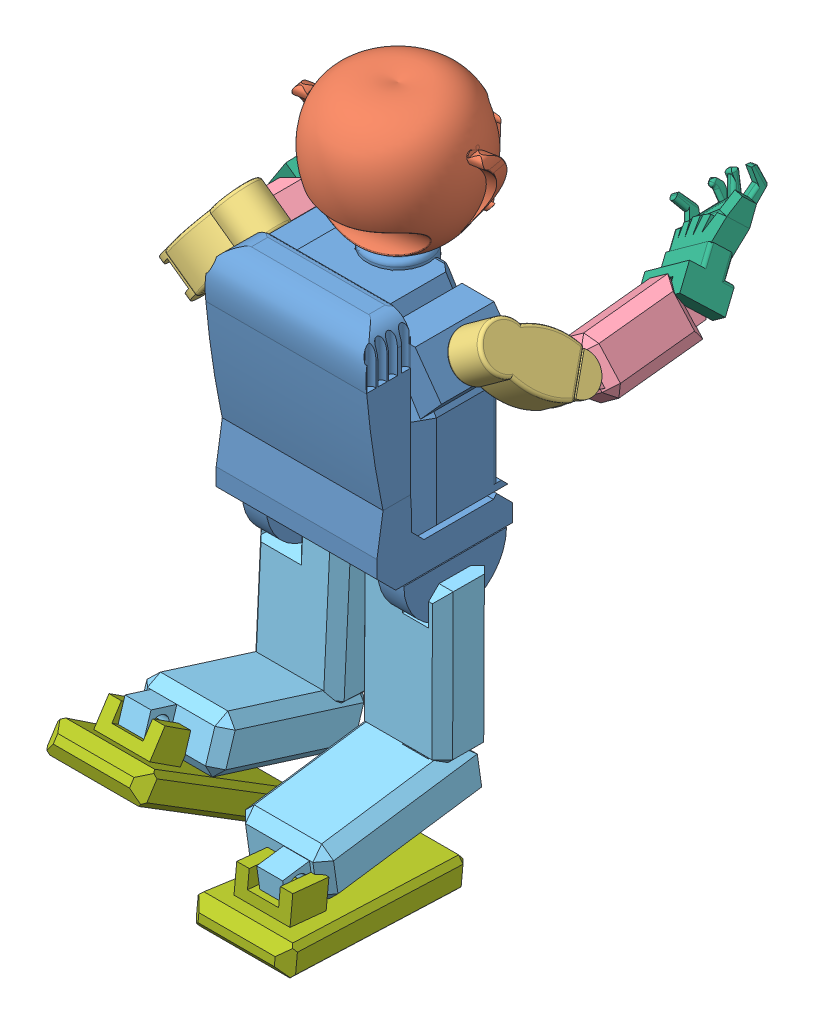
SolidWorks assembly Assem2, configuration Default. Lengths in mm.
Overall size (374.28 631.71 468.66).
14 component instances, 7 part files, 27 mates.
Components (placement in the parent):
- Part3-1: Part3 [Default] at (10.608 -20.5845 -192.5462) size (215.49 271.63 146.25)
- Part1-1: Part1 [Default] at (10.608 181.7095 -178.4472) x (0.182911 0 0.983129) z (-0.983129 0 0.182911) size (177.08 159.74 177.08)
- Part4-1: Part4 [Default] at (113.8396 66.1948 -165.3801) x (0.386781 -0.536178 -0.750275) z (0.811008 0.585035 0) size (102.94 60.36 51.55)
- Part4-2: Part4 [Default] at (-96.5936 60.6913 -146.4531) x (-0.568564 -0.788176 0.235612) z (-0.811008 0.585035 0) size (102.94 60.36 51.55)
- Part5-1: Part5 [Default] at (162.1933 57.4976 -215.127) x (0.583363 -0.808692 -0.075531) z (-0.811008 -0.585035 0) size (51.37 125.6 41.41)
- Part5-2: Part5 [Default] at (-134.9017 23.1874 -142.519) x (-0.584987 -0.810943 -0.01272) z (-0.811008 0.585035 0) size (51.37 125.6 41.41)
- Part6-2: Part6 [Default] at (60.772 -192.5534 -178.723) x (1 0 0) z (0 0.004453 0.99999) size (85 176.15 50)
- Part6-3: Part6 [Default] at (-39.5561 -191.1742 -127.4189) x (-1 0 0) z (0 -0.049279 -0.998785) size (85 176.15 50)
- Part6-4: Part6 [Default] at (61.3239 -314.0436 -93.1319) x (1 0 0) z (0 0.989849 0.14212) size (85 176.15 50)
- Part6-5: Part6 [Default] at (-40.108 -238.5894 -94.7079) x (-1 0 0) z (0 -0.954085 0.299535) size (85 176.15 50)
- Part7-1: Part7 [Default] at (132.6952 72.4721 -310.1946) x (0.811008 0.585035 0) z (0.442514 -0.613438 -0.654122) size (71.55 112.24 41.96)
- Part7-2: Part7 [Default] at (-133.5743 51.6475 -250.1902) x (0.811008 -0.585035 0) z (-0.576708 -0.799466 -0.168113) size (71.55 112.24 41.96)
- Part8-1: Part8 [Default] at (75.4814 -332.0717 -16.4181) x (1 0 0) z (0 0.099495 0.995038) size (95.64 54.98 186.47)
- Part8-2: Part8 [Default] at (-54.2655 -270.1317 -1.563) x (1 0 0) z (0 0.543742 0.839253) size (95.64 54.98 186.47)
Mates (geometry in assembly coordinates):
- Concentric1: concentric: cylinder of Part3-1 through (10.608 108.1735 -178.4472) axis (0 1 0) radius 12; cylinder of Part1-1 through (10.608 109.8979 -178.4472) axis (0 1 0) radius 12
- Concentric3: concentric: cylinder of Part3-1 through (102.1186 73.8965 -149.4154) axis (0.811008 0.585035 0) radius 10; cylinder of Part4-1 through (98.0636 70.9713 -149.4154) axis (0.811008 0.585035 0) radius 10
- Concentric4: concentric: cylinder of Part3-1 through (-76.8476 70.9713 -152.0195) axis (-0.811008 0.585035 0) radius 10; cylinder of Part4-2 through (-76.8476 70.9713 -152.0195) axis (-0.811008 0.585035 0) radius 10
- Concentric5: concentric: cylinder of Part4-1 through (137.3423 38.7419 -206.2509) axis (0.811008 0.585035 0) radius 3; cylinder of Part5-1 through (142.3114 42.3264 -206.2509) axis (0.811008 0.585035 0) radius 5
- Coincident1: coincident: plane of Part4-1 through (132.7421 55.5919 -243.6536) normal (0.811008 0.585035 0); plane of Part5-1 through (142.769 41.6921 -199.1001) normal (-0.811008 -0.585035 0)
- Coincident2: coincident: plane of Part3-1 through (93.0556 95.0067 -188.5462) normal (0.811008 0.585035 0); plane of Part4-1 through (110.3667 71.009 -197.4055) normal (-0.811008 -0.585035 0)
- Coincident3: coincident: plane of Part3-1 through (-71.8396 95.0067 -188.5462) normal (-0.811008 0.585035 0); plane of Part4-2 through (-104.4912 49.7432 -116.8114) normal (0.811008 -0.585035 0)
- Concentric6: concentric: cylinder of Part4-2 through (-129.9988 19.511 -133.6182) axis (-0.811008 0.585035 0) radius 3; cylinder of Part5-2 through (-155.2432 37.7214 -133.6182) axis (0.811008 -0.585035 0) radius 5
- Coincident4: coincident: plane of Part4-2 through (-139.6747 16.5708 -93.5959) normal (-0.811008 0.585035 0); plane of Part5-2 through (-135.1618 22.8269 -126.4324) normal (0.811008 -0.585035 0)
- Coincident5: coincident: plane of Part3-1 through (64.3776 -102.9946 -36.5462) normal (-1 0 0); plane of Part6-2 through (64.3776 -192.3307 -128.7235) normal (1 0 0)
- Parallel1: parallel: plane of Part3-1 through (89.608 -102.8804 -154.5768) normal (1 0 0); plane of Part6-2 through (89.3776 -192.3307 -128.7235) normal (-1 0 0)
- Concentric7: concentric: cylinder of Part3-1 through (89.608 -128.546 -154.7731) axis (-1 0 0) radius 10; cylinder of Part6-2 through (100.3776 -128.546 -154.7731) axis (-1 0 0) radius 10
- Coincident8: coincident: plane of Part3-1 through (-43.1616 -102.9946 -36.5462) normal (1 0 0); plane of Part6-3 through (-43.1616 -193.6381 -177.3581) normal (-1 0 0)
- Concentric9: concentric: cylinder of Part3-1 through (89.608 -128.546 -154.7731) axis (-1 0 0) radius 10; cylinder of Part6-3 through (-79.1616 -128.546 -154.7731) axis (1 0 0) radius 10
- Coincident9: coincident: circle of Part3-1; circle of Part1-1
- Concentric10: concentric: cylinder of Part6-2 through (105.9049 -280.9734 -152.9392) axis (-1 0 0) radius 10; cylinder of Part6-4 through (100.9295 -280.9734 -152.9392) axis (-1 0 0) radius 10
- Coincident11: coincident: plane of Part6-2 through (89.9295 -308.3759 -138.6125) normal (1 0 0); plane of Part6-4 through (89.9295 -264.5511 -86.0259) normal (-1 0 0)
- Concentric11: concentric: cylinder of Part6-3 through (-84.6889 -280.8517 -148.415) axis (1 0 0) radius 10; cylinder of Part6-5 through (-79.7135 -280.8517 -148.415) axis (1 0 0) radius 10
- Coincident12: coincident: plane of Part6-3 through (-68.7135 -308.9844 -161.2488) normal (-1 0 0); plane of Part6-5 through (-68.7135 -286.2937 -79.7312) normal (1 0 0)
- Concentric12: concentric: cylinder of Part5-1 through (204.9532 97.9546 -318.035) axis (-0.811008 -0.585035 0) radius 5; cylinder of Part7-1 through (165.5472 69.5284 -318.035) axis (-0.811008 -0.585035 0) radius 5
- Concentric13: concentric: cylinder of Part5-2 through (-86.8135 -9.8833 -245.7135) axis (-0.811008 0.585035 0) radius 5; cylinder of Part7-2 through (-126.5529 18.7834 -245.7135) axis (-0.811008 0.585035 0) radius 5
- Coincident13: coincident: plane of Part5-2 through (-96.6756 118.3172 -236.2608) normal (-0.811008 0.585035 0); plane of Part7-2 through (-165.4811 22.9352 -242.1282) normal (0.811008 -0.585035 0)
- Concentric14: concentric: cylinder of Part6-4 through (106.4568 -301.494 -1.8883) axis (-1 0 0) radius 10; cylinder of Part8-1 through (95.4814 -301.494 -1.8883) axis (-1 0 0) radius 5
- Coincident14: coincident: plane of Part6-4 through (90.4814 -291.3371 27.3177) normal (1 0 0); plane of Part8-1 through (90.4814 -309.6901 16.5185) normal (-1 0 0)
- Concentric15: concentric: cylinder of Part6-5 through (-85.2408 -236.2944 -2.6339) axis (1 0 0) radius 10; cylinder of Part8-2 through (-34.2655 -236.2944 -2.6339) axis (-1 0 0) radius 5
- Coincident15: coincident: plane of Part6-5 through (-69.2655 -241.6197 27.8258) normal (-1 0 0); plane of Part8-2 through (-69.2655 -235.1604 17.4833) normal (1 0 0)
- Coincident16: coincident: plane of Part5-1 through (99.6356 142.0965 -302.4299) normal (0.811008 0.585035 0); plane of Part7-1 through (161.6858 56.0789 -336.3595) normal (-0.811008 -0.585035 0)
